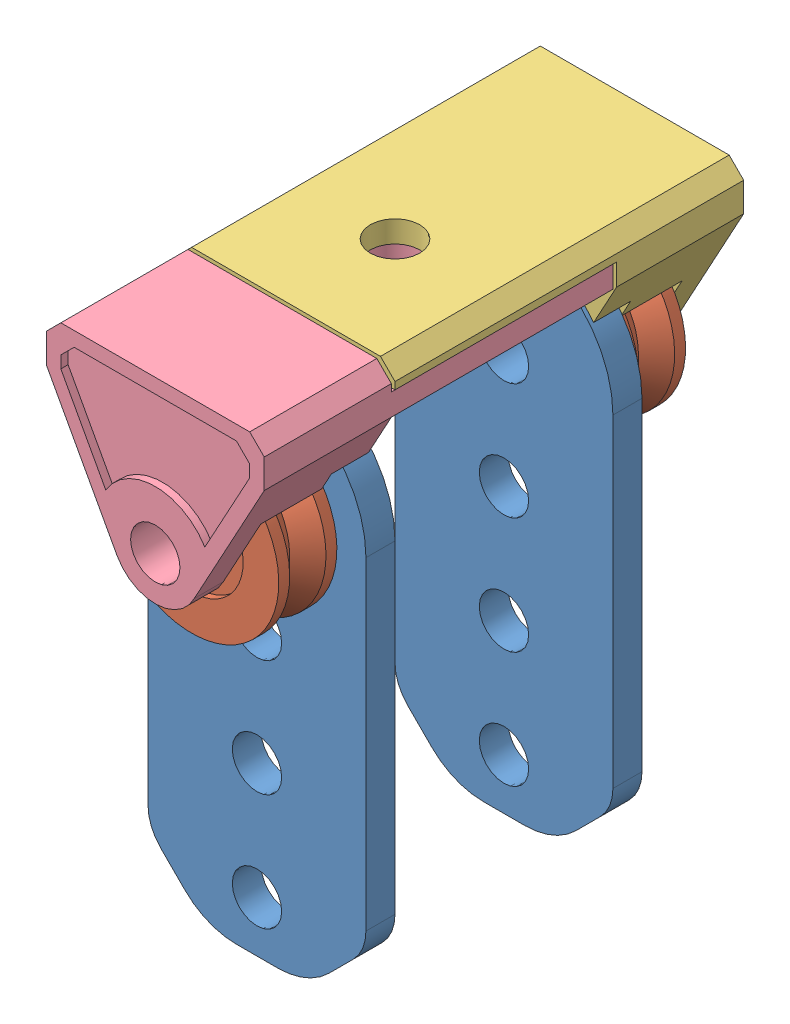
SolidWorks assembly PulleyMountSlides, configuration Default. Lengths in mm.
Overall size (15 38 33).
6 component instances, 4 part files, 22 mates.
Components (placement in the parent):
- pulleyCover2-1: pulleyCover2 [Default] at (4.8643 33.9192 29.7688) size (15 34 2.5)
- REV-41-1368.step-1: REV-41-1368.step [Default] at (4.8643 33.9192 27.2688) size (12 12 4)
- PulleyCoverSlideLeft-1: PulleyCoverSlideLeft [Default] at (4.8643 33.9192 29.5188) x (-1 0 0) z (0 0 -1) size (15 13.5 24)
- REV-41-1368.step-2: REV-41-1368.step [Default] at (4.8643 33.9192 51.2688) size (12 12 4)
- pulleyCover2-2: pulleyCover2 [Default] at (4.8643 33.9192 48.7688) x (-1 0 0) z (0 0 -1) size (15 34 2.5)
- PulleyCoverSliderRight-1: PulleyCoverSliderRight [Default] at (4.8643 33.9192 49.0188) size (15 13.5 24)
Mates (geometry in assembly coordinates):
- InPlace1: in place: plane of pulleyCover2-1 through (4.8643 33.9192 29.7688) normal (0 0 -1); plane of ? through (0 0 29.7688) normal (0 0 -1); moOrthogonalPlaneRef_w of pulleyCover2-1 through (4.8643 33.9192 29.7688) normal (0 0 -1); plane of ? through (0 0 29.7688) normal (0 1 0); plane of pulleyCover2-1 through (4.8643 33.9192 29.7688) normal (0 0 -1); plane of ? through (0 0 29.7688) normal (-1 0 0); plane of pulleyCover2-1 through (4.8643 33.9192 29.7688) normal (0 0 -1); unknown of ?
- Coincident1: coincident: plane of pulleyCover2-1; plane of ?
- Coincident2: coincident: moOrthogonalPlaneRef_w of pulleyCover2-1 through (4.8643 33.9192 29.7688) normal (0 1 0); plane of ? through (4.8643 33.9192 29.7688) normal (0 1 0)
- Coincident3: coincident: moOrthogonalPlaneRef_w of pulleyCover2-1 through (4.8643 33.9192 29.7688) normal (1 0 0); plane of ? through (4.8643 33.9192 29.7688) normal (-1 0 0)
- Coincident4: coincident: plane of pulleyCover2-1 through (4.8643 33.9192 29.2688) normal (0 0 -1); plane of REV-41-1368.step-1 through (4.8643 35.9692 29.2688) normal (0 0 1)
- Concentric1: concentric: cylinder of pulleyCover2-1 through (4.8643 33.9192 31.7688) axis (0 0 -1) radius 1.7; cylinder of REV-41-1368.step-1 through (4.8643 33.9192 27.2688) axis (0 0 -1) radius 1.55
- Concentric2: concentric: cylinder of REV-41-1368.step-1 through (4.8643 33.9192 27.2688) axis (0 0 -1) radius 1.55; cylinder of PulleyCoverSlideLeft-1 through (4.8643 33.9192 22.7688) axis (0 0 1) radius 1.7
- Coincident5: coincident: circle of REV-41-1368.step-1; plane of PulleyCoverSlideLeft-1 through (4.8643 33.9192 25.2688) normal (0 0 1)
- Perpendicular1: perpendicular: plane of pulleyCover2-1 through (12.3643 33.9192 31.7688) normal (1 0 0); plane of PulleyCoverSlideLeft-1 through (12.3643 42.9192 7.694) normal (0 -1 0)
- Coincident7: coincident: plane of PulleyCoverSlideLeft-1 through (12.3643 42.9192 7.694) normal (0 -1 0); plane of ? through (12.3643 42.9192 61.5937) normal (0 1 0)
- Concentric3: concentric: cylinder of PulleyCoverSlideLeft-1 through (4.8643 34.4192 39.0188) axis (0 1 0) radius 1.7; cylinder of ? through (4.8643 44.4192 39.0188) axis (0 -1 0) radius 1.65
- Coincident8: coincident: plane of PulleyCoverSlideLeft-1 through (12.3643 33.9192 43.9375) normal (1 0 0); plane of ? through (12.3643 33.9192 34.1002) normal (1 0 0)
- Coincident9: coincident: plane of REV-41-1368.step-2 through (4.8643 35.4692 49.2688) normal (0 0 -1); plane of pulleyCover2-2 through (4.8643 33.9192 49.2688) normal (0 0 1)
- Coincident10: coincident: plane of REV-41-1368.step-2 through (4.8643 35.9692 52.7688) normal (0 0 1); plane of ? through (4.8643 33.9192 52.7688) normal (0 0 -1)
- Concentric4: concentric: cylinder of REV-41-1368.step-2 through (4.8643 33.9192 51.2688) axis (0 0 -1) radius 1.55; cylinder of pulleyCover2-2 through (4.8643 33.9192 46.7688) axis (0 0 1) radius 1.7
- Concentric5: concentric: cylinder of REV-41-1368.step-2 through (4.8643 33.9192 50.7688) axis (0 0 -1) radius 1.55; cylinder of ? through (4.8643 33.9192 55.2688) axis (0 0 -1) radius 1.7
- Coincident11: coincident: plane of pulleyCover2-1 through (12.3643 33.9192 31.7688) normal (1 0 0); plane of pulleyCover2-2 through (12.3643 33.9192 46.7688) normal (1 0 0)
- Concentric6: concentric: cylinder of PulleyCoverSlideLeft-1 through (4.8643 34.4192 39.2688) axis (0 1 0) radius 1.7; cylinder of PulleyCoverSliderRight-1 through (4.8643 34.4192 39.2688) axis (0 1 0) radius 1.7
- Coincident12: coincident: plane of PulleyCoverSlideLeft-1 through (12.3643 42.9192 7.694) normal (0 -1 0); plane of PulleyCoverSliderRight-1 through (4.8643 42.9192 62.0937) normal (0 1 0)
- Coincident13: coincident: plane of PulleyCoverSlideLeft-1 through (12.3643 33.9192 43.9375) normal (1 0 0); plane of PulleyCoverSliderRight-1 through (12.3643 33.9192 34.6002) normal (1 0 0)
- Concentric7: concentric: cylinder of REV-41-1368.step-2 through (4.8643 33.9192 51.2688) axis (0 0 -1) radius 1.55; cylinder of PulleyCoverSliderRight-1 through (4.8643 33.9192 55.7688) axis (0 0 -1) radius 1.7
- Coincident14: coincident: plane of REV-41-1368.step-2 through (4.8643 35.9692 53.2688) normal (0 0 1); plane of PulleyCoverSliderRight-1 through (4.8643 33.9192 53.2688) normal (0 0 -1)
